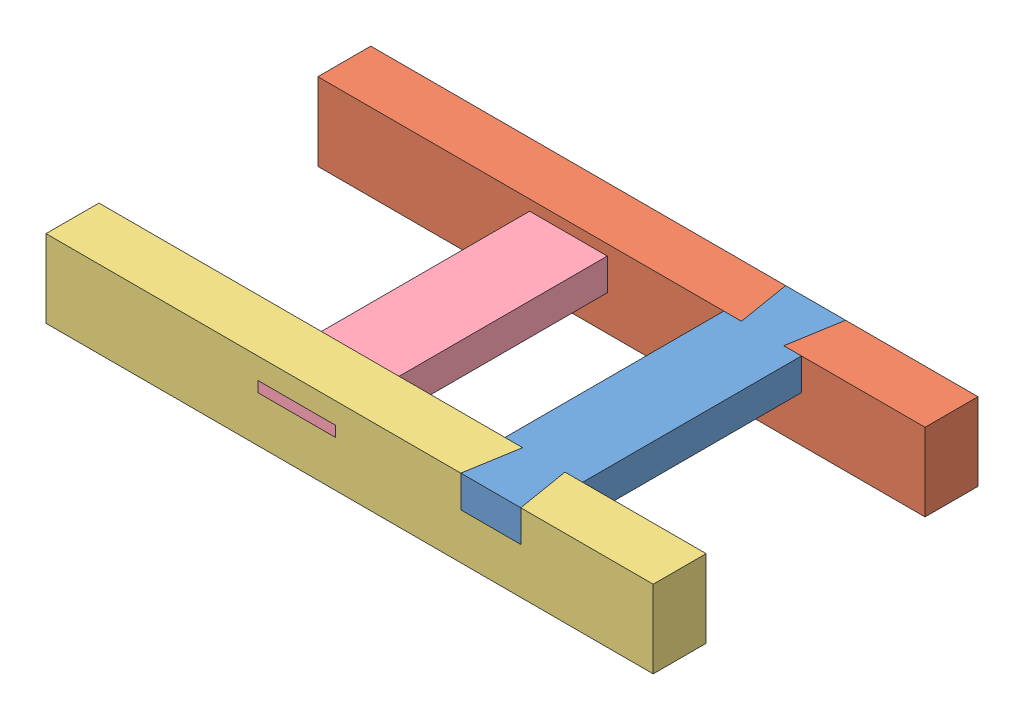
SolidWorks assembly Assem1, configuration Default. Lengths in mm.
Overall size (344 44 184).
4 component instances, 4 part files, 15 mates.
Components (placement in the parent):
- dovetail cross section-1: dovetail cross section [Default] at (10.4329 -283.3472 263.9879) x (0 0 1) z (-1 0 0) size (184 18 44)
- Part1 left base-1: Part1 left base [Default] at (-217.9009 -309.3472 263.9879) size (344 44 30)
- Part2 right base-1: Part2 right base [Default] at (-217.9009 -309.3472 417.9879) size (344 44 30)
- cross mortise and tenon-2: cross mortise and tenon [Default] at (-53.9009 -289.3472 417.9879) x (0 0 -1) z (1 0 0) size (184 18 44)
Mates (geometry in assembly coordinates):
- Coincident6: coincident anti-aligned: plane of Part1 left base-1 through (-217.9009 -309.3472 293.9879) normal (0 0 1); plane of cross mortise and tenon-2 through (-53.9009 -271.3472 293.9879) normal (0 0 -1)
- Coincident8: coincident anti-aligned: plane of Part2 right base-1 through (-217.9009 -309.3472 417.9879) normal (0 0 -1); plane of cross mortise and tenon-2 through (-53.9009 -271.3472 417.9879) normal (0 0 1)
- Coincident12: coincident anti-aligned: plane of dovetail cross section-1 through (12.0991 -265.3472 417.9879) normal (0 0 1); plane of Part2 right base-1 through (-217.9009 -309.3472 417.9879) normal (0 0 -1)
- Concentric1: concentric anti-aligned: cylinder of ? through (-75.9009 -39.3472 355.9879) axis (0 -1 0) radius 6; cylinder of cross mortise and tenon-2 through (-75.9009 -289.3472 355.9879) axis (0 1 0) radius 6
- Coincident15: coincident anti-aligned: plane of dovetail cross section-1 through (10.4329 -283.3472 263.9879) normal (0 -1 0); plane of Part2 right base-1 through (-217.9009 -283.3472 417.9879) normal (0 1 0)
- Coincident16: coincident anti-aligned: plane of dovetail cross section-1 through (46.0991 -265.3472 417.9879) normal (0 0 1); plane of Part2 right base-1 through (-217.9009 -309.3472 417.9879) normal (0 0 -1)
- Coincident17: coincident anti-aligned: plane of dovetail cross section-1 through (51.0979 -265.3472 447.9879) normal (0.986401 0 -0.164359); plane of Part2 right base-1 through (46.0991 -283.3472 417.9879) normal (-0.986401 0 0.164359)
- Concentric2: concentric anti-aligned: cylinder of ? through (-75.9009 -39.3472 355.9879) axis (0 -1 0) radius 6; cylinder of ? through (-75.9009 -271.201 355.9879) axis (0 1 0) radius 5
- Parallel6: parallel anti-aligned: plane of Part1 left base-1 through (-217.9009 -309.3472 263.9879) normal (0 0 -1); plane of ? through (-75.9009 -211.201 475.9879) normal (0 0 1)
- Coincident19: coincident anti-aligned: plane of Part1 left base-1 through (-217.9009 -309.3472 293.9879) normal (0 0 1); plane of cross mortise and tenon-2 through (-53.9009 -271.3472 293.9879) normal (0 0 -1)
- Coincident20: coincident anti-aligned: plane of Part1 left base-1 through (-97.9009 -277.3472 293.9879) normal (0 -1 0); plane of cross mortise and tenon-2 through (-53.9009 -277.3472 263.9879) normal (0 1 0)
- Coincident21: coincident anti-aligned: plane of Part1 left base-1 through (-53.9009 -277.3472 293.9879) normal (-1 0 0); plane of cross mortise and tenon-2 through (-53.9009 -271.3472 417.9879) normal (1 0 0)
- Coincident22: coincident anti-aligned: plane of Part2 right base-1 through (-97.9009 -277.3472 447.9879) normal (0 -1 0); plane of cross mortise and tenon-2 through (-97.9009 -277.3472 447.9879) normal (0 1 0)
- Coincident23: coincident anti-aligned: plane of Part2 right base-1 through (-97.9009 -277.3472 447.9879) normal (1 0 0); plane of cross mortise and tenon-2 through (-97.9009 -271.3472 417.9879) normal (-1 0 0)
- Coincident24: coincident aligned: plane of ? through (-75.9009 -289.3472 355.9879) normal (0 -1 0); plane of cross mortise and tenon-2 through (-53.9009 -289.3472 417.9879) normal (0 -1 0)
